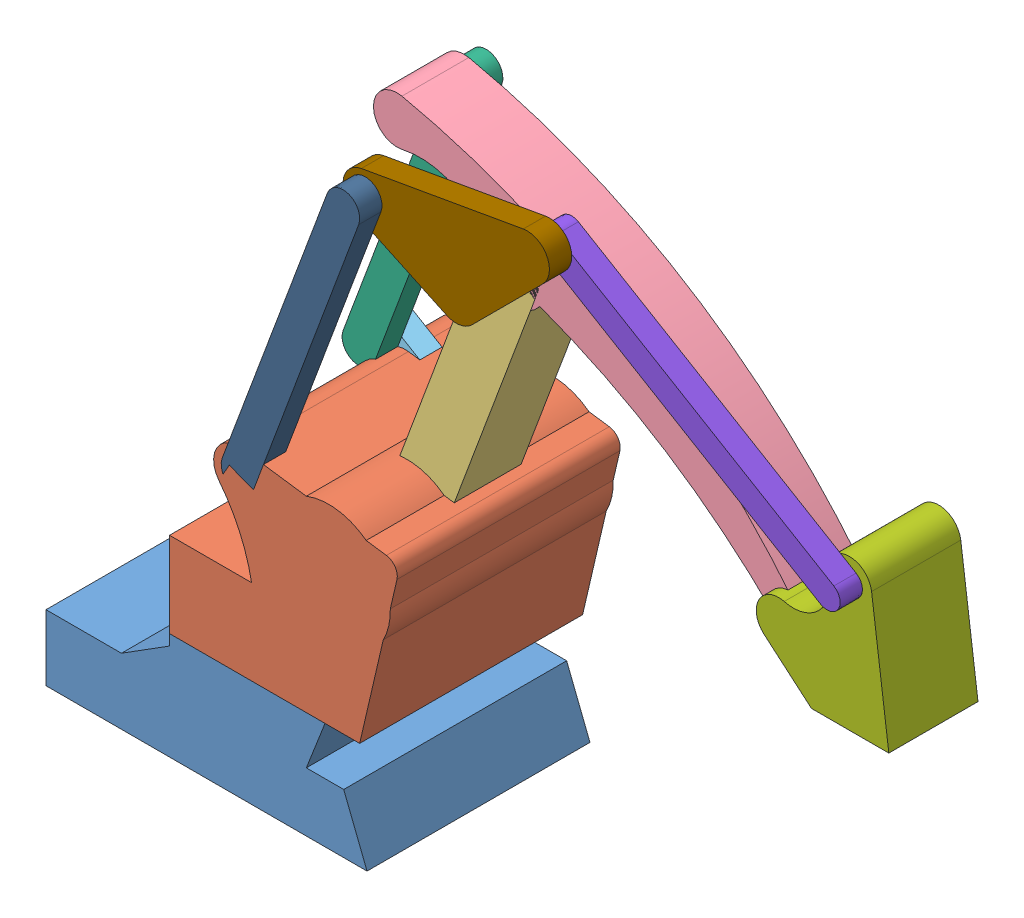
SolidWorks assembly ABB-irb-460逆向工程, configuration 默认. Lengths in mm.
Overall size (348.04 282.3 100).
10 component instances, 10 part files, 22 mates.
Components (placement in the parent):
- （课程结束时保存）（答案）方案-固定底座-1: （课程结束时保存）（答案）方案-固定底座 [默认] at origin size (144 47.96 100)
- （课程结束时保存）（答案）方案-旋转底座-1: （课程结束时保存）（答案）方案-旋转底座 [默认] at origin size (119.66 88.26 100)
- （课程结束时保存）（答案）方案-BC连杆-1: （课程结束时保存）（答案）方案-BC连杆 [默认] at (126.841 106.3205 0) x (0.937015 -0.349289 0) z (0 0 1) size (25 160 30)
- （课程结束时保存）（答案）方案-CD连杆-1: （课程结束时保存）（答案）方案-CD连杆 [默认] at (173.995 232.8175 -15) x (0.920899 -0.3898 0) z (0 0 1) size (220.87 51.05 30)
- （课程结束时保存）（答案）方案-C轴摇杆-1: （课程结束时保存）（答案）方案-C轴摇杆 [默认] at (126.841 106.3205 -35) x (0.859194 -0.51165 0) z (0 0 1) size (75 15 10)
- （课程结束时保存）（答案）方案-C轴连杆-1: （课程结束时保存）（答案）方案-C轴连杆 [默认] at (75.2894 137.0195 -25) x (-0.349289 -0.937015 0) z (0 0 1) size (150 15 10)
- （课程结束时保存）（答案）方案-D轴支架-1: （课程结束时保存）（答案）方案-D轴支架 [默认] at (298.5781 158.6282 -20) size (59.46 67.58 40)
- （课程结束时保存）（答案）0606L1-1: （课程结束时保存）（答案）0606L1 [默认] at (330.3979 190.448 20) x (0.859194 -0.51165 0) z (0 0 1) size (156.65 11.65 10)
- （课程结束时保存）（答案）方案-三角形连杆-1: （课程结束时保存）（答案）方案-三角形连杆 [默认] at (173.995 232.8175 30) x (0.984808 0.173648 0) z (0 0 1) size (93.72 45.81 10)
- （课程结束时保存）（答案）0606L2-1: （课程结束时保存）（答案）0606L2 [默认] at (86.0571 125.3383 40) x (-0.349289 -0.937015 0) z (0 0 1) size (150 15 10)
Mates (geometry in assembly coordinates):
- 重合1: coincident aligned: line of （答案）方案-固定底座-1 through (53.3678 89.661 -18.3061) axis (0 0 1); line of （答案）方案-旋转底座-1 through (53.3678 89.661 -18.3061) axis (0 0 1)
- 重合2: coincident anti-aligned: plane of （答案）方案-固定底座-1 through (125.1562 47.9624 -50.01) normal (0 1 0); plane of （答案）方案-旋转底座-1 through (0 47.9624 50) normal (0 -1 0)
- 同心1: concentric aligned: cylinder of （答案）方案-旋转底座-1 through (126.841 106.3205 50) axis (0 0 -1) radius 27.6011; cylinder of （答案）方案-BC连杆-1 through (126.841 106.3205 15) axis (0 0 -1) radius 12.5
- 宽度1: width aligned: plane of （答案）方案-旋转底座-1 through (0 0 50) normal (0 0 1); plane of （答案）方案-BC连杆-1 through (0 0 -50) normal (0 0 -1); plane of （答案）方案-旋转底座-1 through (126.841 106.3205 15) normal (0 0 1); plane of （答案）方案-BC连杆-1 through (126.841 106.3205 -15) normal (0 0 -1)
- 同心2: concentric aligned: cylinder of （答案）方案-BC连杆-1 through (173.995 232.8175 15) axis (0 0 -1) radius 12.5; cylinder of （答案）方案-CD连杆-1 through (173.995 232.8175 15) axis (0 0 -1) radius 15.8602
- 宽度2: width aligned: plane of （答案）方案-CD连杆-1 through (153.4119 225.7976 15) normal (0 0 1); plane of （答案）方案-BC连杆-1 through (153.4119 225.7976 -15) normal (0 0 -1); plane of （答案）方案-CD连杆-1 through (126.841 106.3205 15) normal (0 0 1); plane of （答案）方案-BC连杆-1 through (126.841 106.3205 -15) normal (0 0 -1)
- 同心3: concentric aligned: cylinder of （答案）方案-旋转底座-1 through (126.841 106.3205 50) axis (0 0 -1) radius 27.6011; cylinder of （答案）方案-C轴摇杆-1 through (126.841 106.3205 -25) axis (0 0 -1) radius 7.5
- 距离1: distance = 10 mm anti-aligned: plane of （答案）方案-CD连杆-1 through (153.4119 225.7976 -15) normal (0 0 -1); plane of （答案）方案-C轴摇杆-1 through (126.841 106.3205 -25) normal (0 0 1)
- 同心4: concentric aligned: cylinder of （答案）方案-C轴摇杆-1 through (75.2894 137.0195 -25) axis (0 0 -1) radius 7.5; cylinder of （答案）方案-C轴连杆-1 through (75.2894 137.0195 -15) axis (0 0 -1) radius 7.5
- 平行1: parallel aligned: plane of （答案）方案-固定底座-1 through (0 0 50) normal (0 0 1); plane of （答案）方案-旋转底座-1 through (0 0 50) normal (0 0 1)
- 重合3: coincident anti-aligned: plane of （答案）方案-CD连杆-1 through (153.4119 225.7976 -15) normal (0 0 -1); plane of （答案）方案-C轴连杆-1 through (75.2894 137.0195 -15) normal (0 0 1)
- 同心5: concentric aligned: cylinder of （答案）方案-CD连杆-1 through (122.4434 263.5165 15) axis (0 0 -1) radius 10.5842; cylinder of （答案）方案-C轴连杆-1 through (122.4434 263.5165 -15) axis (0 0 -1) radius 7.5
- 同心6: concentric aligned: cylinder of （答案）方案-CD连杆-1 through (298.5781 158.6282 15) axis (0 0 -1) radius 7.1987; cylinder of （答案）方案-D轴支架-1 through (298.5781 158.6282 20) axis (0 0 -1) radius 10
- 宽度3: width aligned: plane of （答案）方案-D轴支架-1 through (298.5781 158.6282 20) normal (0 0 1); plane of （答案）方案-CD连杆-1 through (298.5781 158.6282 -20) normal (0 0 -1); plane of （答案）方案-D轴支架-1 through (153.4119 225.7976 15) normal (0 0 1); plane of （答案）方案-CD连杆-1 through (153.4119 225.7976 -15) normal (0 0 -1)
- 同心7: concentric aligned: cylinder of （答案）方案-D轴支架-1 through (330.3979 190.448 20) axis (0 0 -1) radius 10; cylinder of （答案）0606L1-1 through (330.3979 190.448 30) axis (0 0 -1) radius 5.8253
- 重合4: coincident anti-aligned: plane of （答案）方案-D轴支架-1 through (298.5781 158.6282 20) normal (0 0 1); plane of （答案）0606L1-1 through (205.8148 264.6373 20) normal (0 0 -1)
- 同心8: concentric aligned: cylinder of （答案）方案-CD连杆-1 through (173.995 232.8175 15) axis (0 0 -1) radius 15.8602; cylinder of （答案）方案-三角形连杆-1 through (173.995 232.8175 40) axis (0 0 -1) radius 10
- 重合6: coincident anti-aligned: plane of （答案）0606L1-1 through (205.8148 264.6373 30) normal (0 0 1); plane of （答案）方案-三角形连杆-1 through (133.2112 251.8353 30) normal (0 0 -1)
- 同心9: concentric aligned: cylinder of （答案）0606L1-1 through (205.8148 264.6373 30) axis (0 0 -1) radius 5.8253; cylinder of （答案）方案-三角形连杆-1 through (205.8148 264.6373 40) axis (0 0 -1) radius 10
- 同心10: concentric aligned: cylinder of （答案）方案-三角形连杆-1 through (133.2112 251.8353 40) axis (0 0 -1) radius 10; cylinder of （答案）0606L2-1 through (133.2112 251.8353 50) axis (0 0 -1) radius 7.5
- 同心11: concentric aligned: cylinder of （答案）方案-旋转底座-1 through (86.0571 125.3383 50) axis (0 0 -1) radius 10.8815; cylinder of （答案）0606L2-1 through (86.0571 125.3383 50) axis (0 0 -1) radius 7.5
- 重合7: coincident anti-aligned: plane of （答案）方案-三角形连杆-1 through (133.2112 251.8353 40) normal (0 0 1); plane of （答案）0606L2-1 through (86.0571 125.3383 40) normal (0 0 -1)
